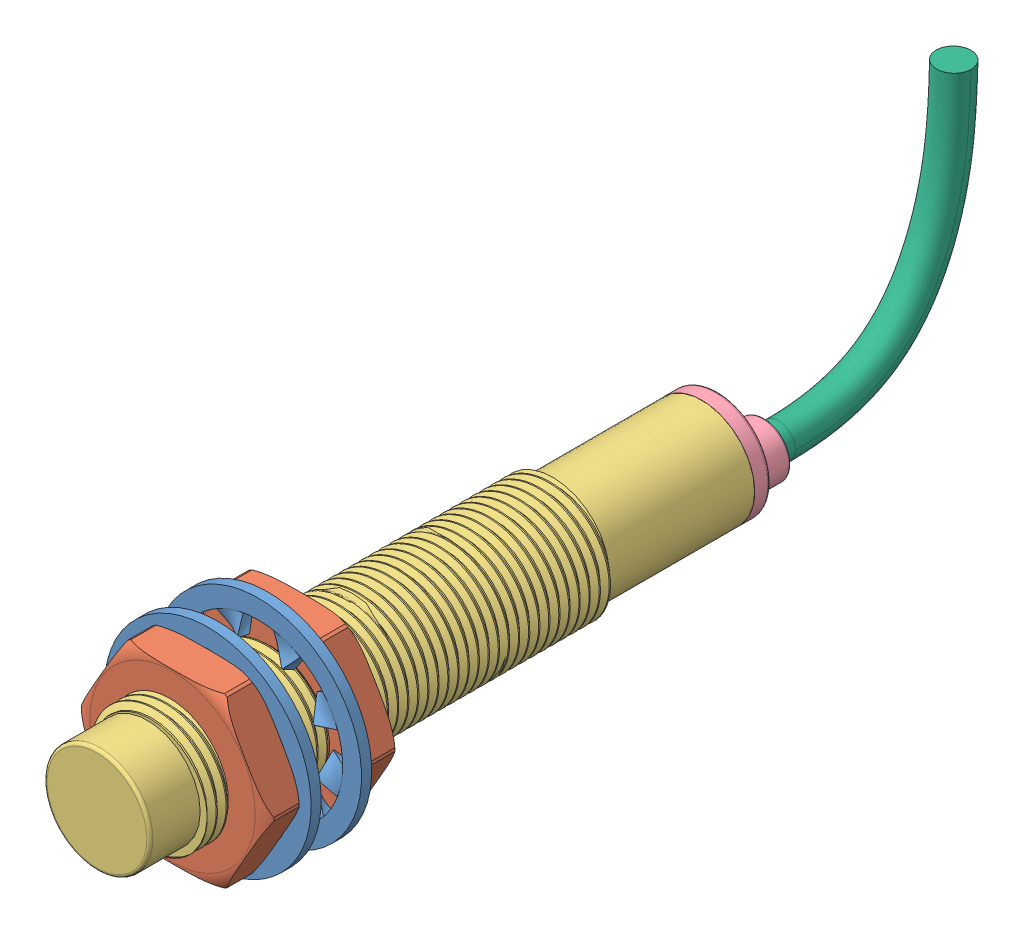
SolidWorks assembly Inductive_sensor, configuration Default. Lengths in mm.
Overall size (20.5 32.31 86.91).
9 component instances, 6 part files, 0 mates.
Components (placement in the parent):
- LJ12A3-4-Z_BX v6.step-1: LJ12A3-4-Z_BX v6.step [Default] at origin size (20.5 32.31 86.91)
  - 93925A300.step-1: 93925A300.step [Default] at (-0.0005 -0.0003 -11.5) x (1 0 0) z (0 0 -1) size (20.5 20.5 2.11)
  - 93925A300.step-2: 93925A300.step [Default] at (-0.0006 -0.0007 -16.5) x (1 0 0) z (0 0 -1) size (20.5 20.5 2.11)
  - Nut.step-1: Nut.step [Default] at (-0.0001 -0.0008 -11) size (19.14 16.74 3.53)
  - Nut.step-2: Nut.step [Default] at (-0.0004 -0.0002 -17) x (1 0 0) z (0 0 -1) size (19.14 16.74 3.53)
  - LJ12A3-4-Z_BX.step-1: LJ12A3-4-Z_BX.step [Default] at origin size (13.73 13.36 60)
  - LJ12A3-4-Z_BX-0.step-1: LJ12A3-4-Z_BX-0.step [Default] at origin size (10.5 10.5 6.2)
  - LJ12A3-4-Z_BX-1.step-1: LJ12A3-4-Z_BX-1.step [Default] at origin size (3.5 3.5 1.5)
  - LJ12A3-4-Z_BX-2.step-1: LJ12A3-4-Z_BX-2.step [Default] at origin size (3.54 25.97 25.31)
